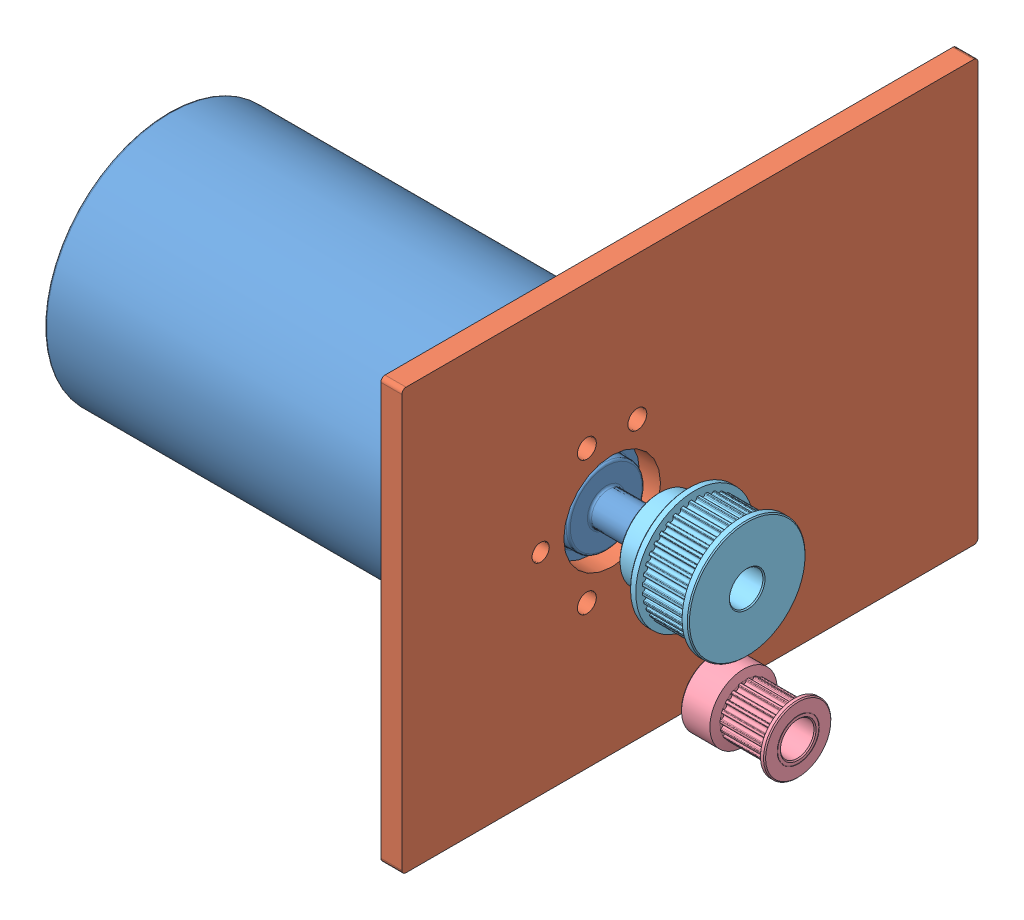
SolidWorks assembly Motor_ASS, configuration Standard. Lengths in mm.
Overall size (155.4 100 137).
10 component instances, 5 part files, 5 mates.
Components (placement in the parent):
- DC_Motor_CPB_I-1: DC_Motor_CPB_I [Standard] at (-35.8887 8.3642 0) size (142 59 59)
- Motor_Konsole-1: Motor_Konsole [Standard] at (42.9202 -1.544 -142) size (5 100 137)
- GT2 Timing Pulley 20T 10mm - Bore_8mm.step-2: GT2 Timing Pulley 20T 10mm - Bore_8mm.step [Standard] at (73.3182 -28.4426 -11.8541) x (0 -0.924225 -0.381849) z (1 0 0) size (16.01 16.01 20)
  - M4x0.7X4mm - flat-tip Set screw.step-1: M4x0.7X4mm - flat-tip Set screw.step [Standard] at (0 6.0086 -9.25) x (1 0 0) z (0 1 0) size (5.52 5.51 4)
  - M4x0.7X4mm - flat-tip Set screw.step-2: M4x0.7X4mm - flat-tip Set screw.step [Standard] at (6.0086 0 -9.25) x (0 0 1) z (1 0 0) size (5.52 5.51 4)
  - GT2 Timing Pulley 20T 10mm - Hole_8mm.step-1: GT2 Timing Pulley 20T 10mm - Hole_8mm.step [Standard] at origin size (16.01 16.01 20)
- GT2 Timing Pulley 40T 10mm - Bore_8mm.step-1: GT2 Timing Pulley 40T 10mm - Bore_8mm.step [Standard] at (67.545 8.3642 0) x (0 0.006446 -0.999979) z (1 0 0) size (28 28 21)
  - M4x0.7X4mm - flat-tip Set screw.step-1: M4x0.7X4mm - flat-tip Set screw.step [Standard] at (0 -7.5014 -5) x (1 0 0) z (0 -1 0) size (5.52 5.51 4)
  - M4x0.7X4mm - flat-tip Set screw.step-2: M4x0.7X4mm - flat-tip Set screw.step [Standard] at (7.5014 0 -5) x (0 0 1) z (1 0 0) size (5.52 5.51 4)
  - GT2 Timing Pulley 40T 10mm - Bore_8mm.step-1: GT2 Timing Pulley 40T 10mm - Bore_8mm.step [Standard] at origin size (28 28 21)
Mates (geometry in assembly coordinates):
- Konzentrisch1: concentric anti-aligned: cylinder of DC_Motor_CPB_I-1 through (-35.8887 8.3642 0) axis (1 0 0) radius 9.0539; cylinder of Motor_Konsole-1 through (47.9202 8.3642 0) axis (-1 0 0) radius 11.5
- Deckungsgleich1: coincident anti-aligned: plane of DC_Motor_CPB_I-1 through (42.9202 33.7618 0) normal (1 0 0); plane of Motor_Konsole-1 through (42.9202 -1.544 -142) normal (-1 0 0)
- Konzentrisch2: concentric anti-aligned: cylinder of DC_Motor_CPB_I-1 through (42.9202 24.2702 6) axis (1 0 0) radius 2; cylinder of Motor_Konsole-1 through (47.9202 24.2702 6) axis (-1 0 0) radius 2.25
- Deckungsgleich3: coincident aligned: plane of DC_Motor_CPB_I-1 through (-35.8887 8.3642 0) normal (0 0 1)
- Konzentrisch4: concentric anti-aligned: cylinder of DC_Motor_CPB_I-1 through (-35.8887 8.3642 0) axis (1 0 0) radius 4; cylinder of GT2 Timing Pulley 40T 10mm - Bore_8mm.step-1/GT2 Timing Pulley 40T 10mm - Bore_8mm.step-1 through (68.495 8.3642 0) axis (-1 0 0) radius 4
